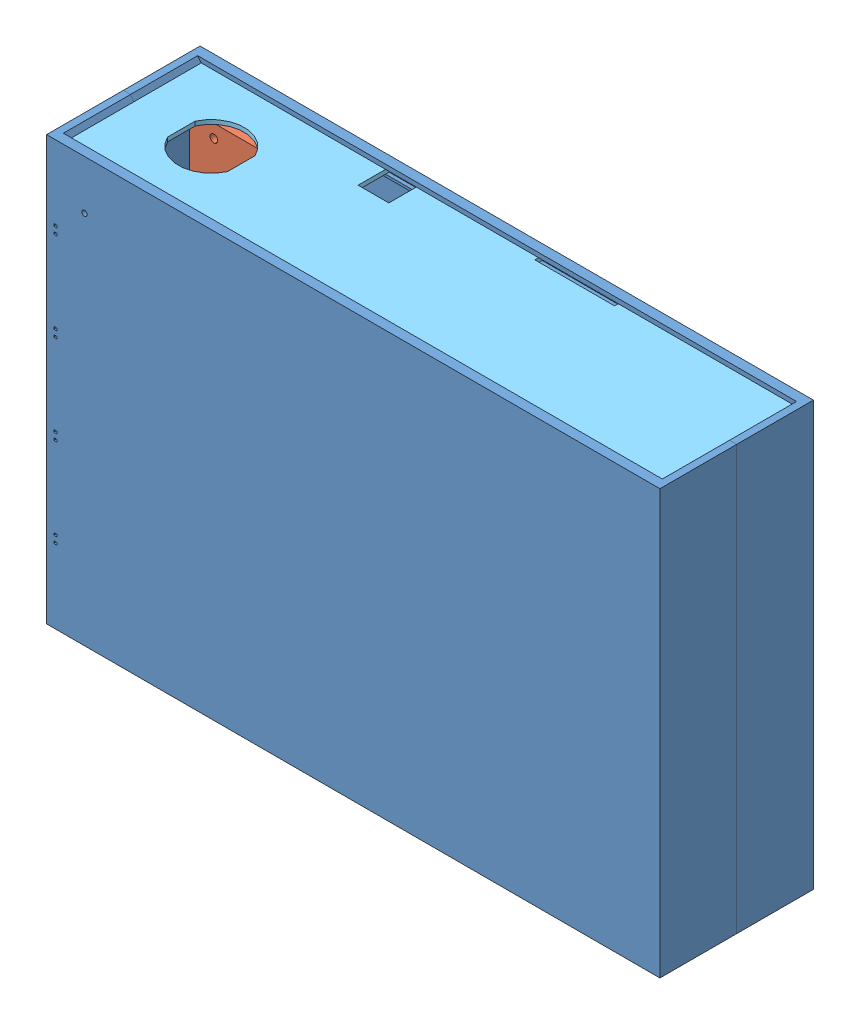
SolidWorks assembly box asm, configuration Default. Lengths in mm.
Overall size (260.1 179.71 65.07).
8 component instances, 7 part files, 23 mates.
Components (placement in the parent):
- box base 3D-1: box base 3D [Default] at (59.1951 130.5794 223.1417) size (260.1 179.71 32.54)
- USB plate-1: USB plate [Default] at (59.3475 130.5794 233.3271) x (-1 0 0) z (0 0 -1) size (248.92 149.22 3.17)
- box base 3D-2: box base 3D [Default] at (59.1951 130.5794 288.2165) x (1 0 0) z (0 0 -1) size (260.1 179.71 32.54)
- isolation plate-1: isolation plate [Default] at (59.3475 130.5794 281.2061) x (-1 0 0) z (0 0 -1) size (248.92 149.22 3.17)
- side panel bnc-1: side panel bnc [Default] at (-67.8049 42.6319 286.2607) x (1 0 0) z (0 1 0) size (254 60.07 1.78)
- side panel ribbon power usb-1: side panel ribbon power usb [Default] at (186.1951 216.7489 225.6817) x (-1 0 0) z (0 1 0) size (254 60.07 1.78)
- isolation board-1: isolation board [Default] at (92.6977 171.8417 268.0235) x (1 0 0) z (0 -1 0) size (126.83 1.63 73.54)
- Samtec-ERM8-040-01-L-D-RA-1: Samtec-ERM8-040-01-L-D-RA [LEAD STYLE1PLATINGLPOSITIONS40ROWDTAIL SPECIFICATIONRA] at (94.2532 192.5917 273.0991) x (-1 0 0) z (0 1 0) size (45 7.93 15.36)
Mates (geometry in assembly coordinates):
- Coincident1: coincident anti-aligned: plane of box base 3D-1 through (59.1951 130.5794 230.1521) normal (0 0 1); line of USB plate-1 through (183.8075 205.1919 230.1521) axis (0 -1 0)
- Coincident2: coincident anti-aligned: plane of box base 3D-1 through (59.1951 130.5794 255.6791) normal (0 0 1); plane of box base 3D-2 through (59.1951 130.5794 255.6791) normal (0 0 -1)
- Coincident3: coincident aligned: plane of box base 3D-1 through (189.2431 130.5794 226.1897) normal (1 0 0); plane of box base 3D-2 through (189.2431 130.5794 285.1685) normal (1 0 0)
- Coincident4: coincident aligned: plane of box base 3D-1 through (59.1951 220.4319 226.1897) normal (0 1 0); plane of box base 3D-2 through (59.1951 220.4319 285.1685) normal (0 1 0)
- Concentric5: concentric anti-aligned: cylinder of box base 3D-1 through (-54.8001 61.593 230.1521) axis (0 0 -1) radius 2.7686; cylinder of USB plate-1 through (-54.8001 61.593 233.3271) axis (0 0 1) radius 1.632
- Concentric6: concentric anti-aligned: cylinder of box base 3D-1 through (21.2983 61.593 230.1521) axis (0 0 -1) radius 2.7686; cylinder of USB plate-1 through (21.2983 61.593 233.3271) axis (0 0 1) radius 1.632
- Concentric7: concentric aligned: cylinder of box base 3D-2 through (-54.8001 199.5658 281.2061) axis (0 0 1) radius 2.7686; cylinder of isolation plate-1 through (-54.8001 199.5658 281.2061) axis (0 0 1) radius 1.632
- Concentric8: concentric aligned: cylinder of box base 3D-2 through (-54.8001 61.593 281.2061) axis (0 0 1) radius 2.7686; cylinder of isolation plate-1 through (-54.8001 61.593 281.2061) axis (0 0 1) radius 1.632
- Coincident6: coincident anti-aligned: plane of box base 3D-2 through (59.1951 130.5794 281.2061) normal (0 0 -1); plane of isolation plate-1 through (59.3475 130.5794 281.2061) normal (0 0 1)
- Coincident7: coincident anti-aligned: plane of box base 3D-1 through (59.1951 216.7489 255.6791) normal (0 1 0); plane of side panel ribbon power usb-1 through (186.1951 216.7489 225.6817) normal (0 -1 0)
- Coincident10: coincident anti-aligned: plane of box base 3D-1 through (59.1951 130.5794 226.1897) normal (0 0 1); plane of side panel bnc-1 through (-67.8049 44.4099 226.1897) normal (0 0 -1)
- Coincident11: coincident anti-aligned: plane of box base 3D-1 through (-67.8049 130.5794 255.6791) normal (1 0 0); plane of side panel bnc-1 through (-67.8049 44.4099 286.2607) normal (-1 0 0)
- Coincident12: coincident anti-aligned: plane of box base 3D-1 through (186.1951 130.5794 255.6791) normal (-1 0 0); plane of side panel ribbon power usb-1 through (186.1951 218.5269 225.6817) normal (1 0 0)
- Coincident14: coincident anti-aligned: plane of box base 3D-1 through (59.1951 130.5794 225.6817) normal (0 0 1); plane of side panel ribbon power usb-1 through (186.1951 218.5269 225.6817) normal (0 0 -1)
- Distance1: distance = 8.382 mm anti-aligned: plane of isolation board-1 through (92.6977 171.8417 269.6491) normal (0 0 1); plane of isolation plate-1 through (59.3475 130.5794 278.0311) normal (0 0 -1)
- Concentric9: concentric anti-aligned: cylinder of isolation plate-1 through (36.3097 199.1467 281.2061) axis (0 0 1) radius 1.016; cylinder of isolation board-1 through (36.3097 199.1467 268.0235) axis (0 0 -1) radius 1.632
- Parallel2: parallel aligned: plane of isolation board-1 through (92.6977 203.5917 269.6491) normal (0 1 0); plane of isolation plate-1 through (183.8075 205.1919 278.0311) normal (0 1 0)
- Coincident19: coincident anti-aligned: plane of isolation board-1 through (92.6977 171.8417 269.6491) normal (0 0 1); plane of Samtec-ERM8-040-01-L-D-RA-1 through (116.7532 207.9517 269.6491) normal (0 0 -1)
- Coincident20: coincident aligned: plane of isolation board-1 through (92.6977 203.5917 269.6491) normal (0 1 0); plane of Samtec-ERM8-040-01-L-D-RA-1 through (116.7532 203.5917 269.6491) normal (0 1 0)
- Coincident24: coincident anti-aligned: plane of Samtec-ERM8-040-01-L-D-RA-1 through (116.7532 203.5917 269.6491) normal (0 1 0); plane of ? through (114.0632 203.5917 275.7816) normal (0 -1 0)
- Coincident25: coincident anti-aligned: plane of Samtec-ERM8-040-01-L-D-RA-1 through (112.3532 203.5917 274.6616) normal (0 0 1); plane of ? through (76.1532 179.9417 274.6616) normal (0 0 -1)
- Coincident26: coincident anti-aligned: plane of Samtec-ERM8-040-01-L-D-RA-1 through (76.1532 203.5917 274.6616) normal (-1 0 0); plane of ? through (76.1532 179.9417 274.6616) normal (1 0 0)
- Coincident27: coincident anti-aligned: plane of box base 3D-1 through (59.1951 44.4099 255.6791) normal (0 -1 0); plane of side panel bnc-1 through (-67.8049 44.4099 286.2607) normal (0 1 0)
